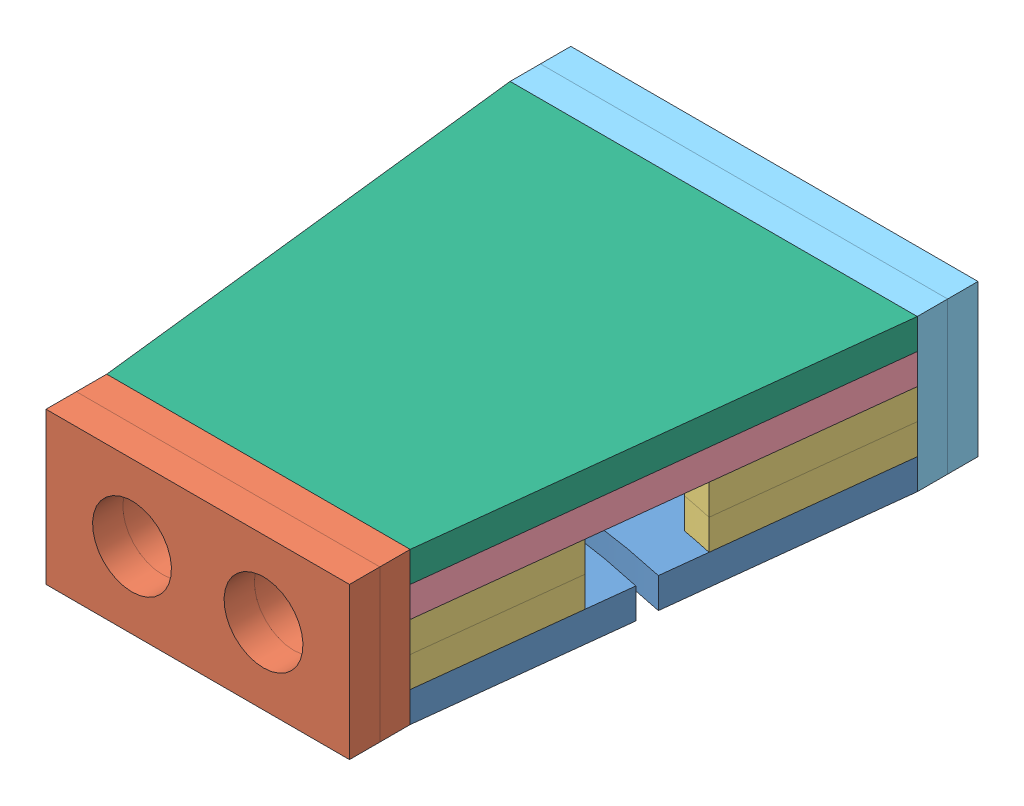
SolidWorks assembly housing, configuration Default. Lengths in mm.
Overall size (40.25 15 57).
9 component instances, 6 part files, 24 mates.
Components (placement in the parent):
- housing-bottom-1: housing-bottom [Default] at (19.3006 18.161 112.8173) size (40.25 3 45)
- housing-inside-1: housing-inside [Default] at (19.3006 25.661 58.3173) x (1 0 0) z (0 -1 0) size (30 3 15)
- housing-middle-bottom-1: housing-middle-bottom [Default] at (19.3006 21.161 112.8173) size (40.25 3 45)
- housing-middle-top-1: housing-middle-top [Default] at (19.3006 27.161 112.8173) size (40.25 3 45)
- housing-outside-1: housing-outside [Default] at (19.3027 25.661 10.3173) x (1 0 0) z (0 -1 0) size (40.25 3 15)
- housing-top-1: housing-top [Default] at (19.3006 30.161 112.8173) size (40.25 3 45)
- housing-middle-bottom-2: housing-middle-bottom [Default] at (19.3006 24.161 112.8173) size (40.25 3 45)
- housing-inside-2: housing-inside [Default] at (19.3006 25.661 61.3173) x (1 0 0) z (0 -1 0) size (30 3 15)
- housing-outside-2: housing-outside [Default] at (19.3027 25.661 7.3173) x (1 0 0) z (0 -1 0) size (40.25 3 15)
Mates (geometry in assembly coordinates):
- Coincident1: coincident anti-aligned: plane of housing-bottom-1 through (19.3006 21.161 112.8173) normal (0 1 0); plane of housing-middle-bottom-1 through (19.3006 21.161 112.8173) normal (0 -1 0)
- Coincident2: coincident aligned: plane of housing-bottom-1 through (19.3006 21.161 58.3173) normal (0 0 1); plane of housing-middle-bottom-1 through (19.3006 24.161 58.3173) normal (0 0 1)
- Coincident3: coincident aligned: plane of housing-bottom-1 through (39.4277 21.161 13.3173) normal (0.993572 0 0.113203); plane of housing-middle-bottom-1 through (39.4277 24.161 13.3173) normal (0.993572 0 0.113203)
- Coincident4: coincident anti-aligned: plane of housing-middle-bottom-1 through (19.3006 24.161 112.8173) normal (0 1 0); plane of housing-middle-bottom-2 through (19.3006 24.161 112.8173) normal (0 -1 0)
- Coincident5: coincident aligned: plane of housing-middle-bottom-1 through (19.3006 24.161 58.3173) normal (0 0 1); plane of housing-middle-bottom-2 through (19.3006 27.161 58.3173) normal (0 0 1)
- Coincident6: coincident aligned: plane of housing-middle-bottom-1 through (39.4277 24.161 13.3173) normal (0.993572 0 0.113203); plane of housing-middle-bottom-2 through (39.4277 27.161 13.3173) normal (0.993572 0 0.113203)
- Coincident7: coincident anti-aligned: plane of housing-middle-top-1 through (19.3006 27.161 112.8173) normal (0 -1 0); plane of housing-middle-bottom-2 through (19.3006 27.161 112.8173) normal (0 1 0)
- Coincident8: coincident aligned: plane of housing-middle-top-1 through (19.3006 30.161 58.3173) normal (0 0 1); plane of housing-middle-bottom-2 through (19.3006 27.161 58.3173) normal (0 0 1)
- Coincident9: coincident aligned: plane of housing-middle-top-1 through (-0.8265 30.161 13.3173) normal (-0.993572 0 0.113203); plane of housing-middle-bottom-2 through (-0.8265 27.161 13.3173) normal (-0.993572 0 0.113203)
- Coincident10: coincident anti-aligned: plane of housing-middle-top-1 through (19.3006 30.161 112.8173) normal (0 1 0); plane of housing-top-1 through (19.3006 30.161 112.8173) normal (0 -1 0)
- Coincident11: coincident aligned: plane of housing-middle-top-1 through (19.3006 30.161 58.3173) normal (0 0 1); plane of housing-top-1 through (19.3006 33.161 58.3173) normal (0 0 1)
- Coincident12: coincident aligned: plane of housing-middle-top-1 through (39.4277 30.161 13.3173) normal (0.993572 0 0.113203); plane of housing-top-1 through (39.4277 33.161 13.3173) normal (0.993572 0 0.113203)
- Coincident13: coincident anti-aligned: plane of housing-inside-1 through (19.3006 25.661 58.3173) normal (0 0 -1); plane of housing-top-1 through (19.3006 33.161 58.3173) normal (0 0 1)
- Coincident14: coincident aligned: plane of housing-bottom-1 through (19.3006 18.161 112.8173) normal (0 -1 0); plane of housing-inside-1 through (4.3006 18.161 61.3173) normal (0 -1 0)
- Coincident15: coincident: point of housing-inside-1; point of housing-top-1
- Coincident16: coincident anti-aligned: plane of housing-outside-1 through (19.3027 25.661 13.3173) normal (0 0 1); plane of housing-top-1 through (-0.8265 33.161 13.3173) normal (0 0 -1)
- Coincident17: coincident aligned: plane of housing-bottom-1 through (19.3006 18.161 112.8173) normal (0 -1 0); plane of housing-outside-1 through (-0.8223 18.161 13.3173) normal (0 -1 0)
- Coincident18: coincident: point of housing-outside-1; point of housing-top-1
- Coincident19: coincident anti-aligned: plane of housing-outside-1 through (19.3027 25.661 10.3173) normal (0 0 -1); plane of housing-outside-2 through (19.3027 25.661 10.3173) normal (0 0 1)
- Coincident20: coincident aligned: plane of housing-outside-1 through (-0.8223 18.161 13.3173) normal (-1 0 0); plane of housing-outside-2 through (-0.8223 18.161 10.3173) normal (-1 0 0)
- Coincident21: coincident aligned: plane of housing-outside-1 through (-0.8223 33.161 13.3173) normal (0 1 0); plane of housing-outside-2 through (-0.8223 33.161 10.3173) normal (0 1 0)
- Coincident22: coincident anti-aligned: plane of housing-inside-1 through (19.3006 25.661 61.3173) normal (0 0 1); plane of housing-inside-2 through (19.3006 25.661 61.3173) normal (0 0 -1)
- Coincident23: coincident aligned: plane of housing-inside-1 through (4.3006 33.161 61.3173) normal (0 1 0); plane of housing-inside-2 through (4.3006 33.161 64.3173) normal (0 1 0)
- Coincident24: coincident aligned: plane of housing-inside-1 through (34.3006 18.161 61.3173) normal (1 0 0); plane of housing-inside-2 through (34.3006 18.161 64.3173) normal (1 0 0)
